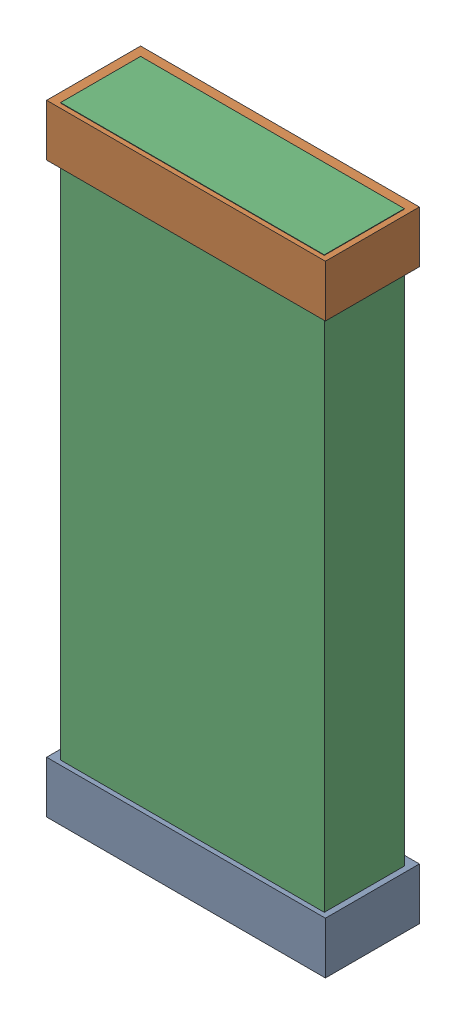
SolidWorks assembly C6, configuration Default. Lengths in mm.
Overall size (1.48 3.3 0.5).
6 component instances, 2 part files, 0 mates.
Components (placement in the parent):
- 744579568_4-1: 744579568_4 [Default] at (38.5899 23.3899 -0.9115) size (1.48 0.28 0.5)
  - Extruded (21)-1: Extruded (21) [Default] at origin size (1.48 0.28 0.5)
- 744579568_5-1: 744579568_5 [Default] at (38.5899 26.4101 -0.9115) size (1.48 0.28 0.5)
  - Extruded (21)-1: Extruded (21) [Default] at origin size (1.48 0.28 0.5)
- 744579440_2-1: 744579440_2 [Default] at (38.6 24.915 -0.8615) size (1.4 3.27 0.42)
  - Extruded (22)-1: Extruded (22) [Default] at origin size (1.4 3.27 0.42)
